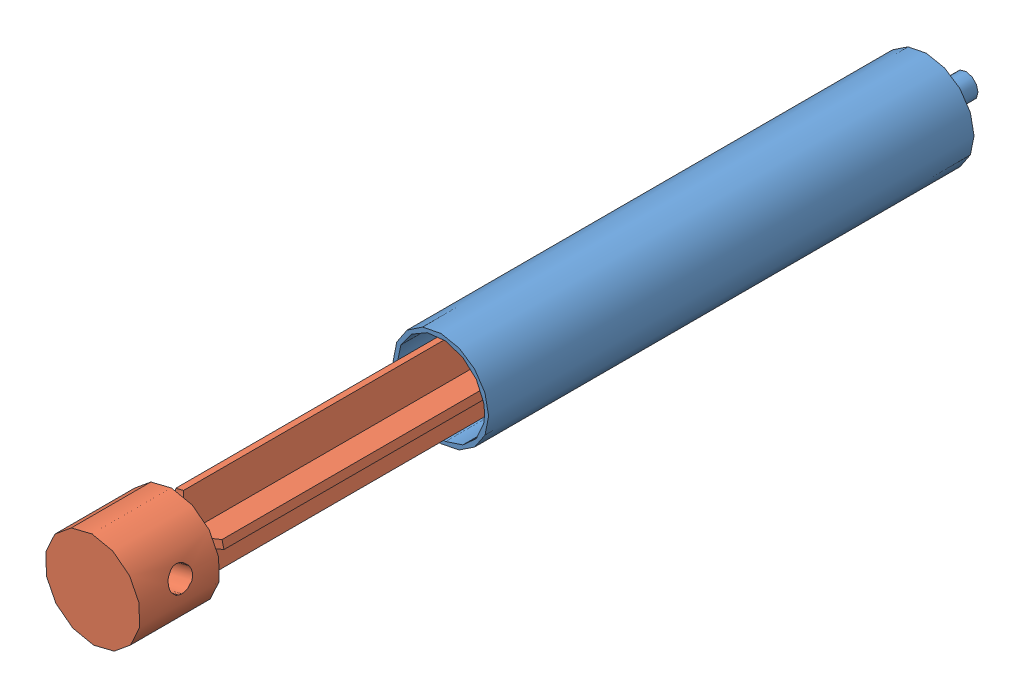
SolidWorks assembly syringe-base, configuration Default. Lengths in mm.
Overall size (18.45 18.45 139.39).
2 component instances, 2 part files, 3 mates.
Components (placement in the parent):
- sr-cylinder-1: sr-cylinder [Default] at (30.2101 49.0436 27.0158) size (15.24 15.24 83.82)
- sr-plunger-1: sr-plunger [Default] at (30.2101 49.0436 59.7213) x (-0.970784 -0.239954 0) z (0 0 1) size (15.24 15.24 99.06)
Mates (geometry in assembly coordinates):
- Concentric1: concentric aligned: cylinder of sr-cylinder-1 through (30.2101 49.0436 103.2158) axis (0 0 -1) radius 6.985; cylinder of sr-plunger-1 through (30.2101 49.0436 62.2613) axis (0 0 -1) radius 6.985
- LimitDistance1: limit distance = 32.7055 mm anti-aligned: plane of sr-plunger-1 through (30.2101 49.0436 59.7213) normal (0 0 -1); plane of sr-cylinder-1 through (30.2101 49.0436 27.0158) normal (0 0 1)
- Concentric2: concentric aligned: cylinder of sr-cylinder-1 through (30.2101 49.0436 103.2158) axis (0 0 -1) radius 7.62; cylinder of sr-plunger-1 through (30.2101 49.0436 158.7813) axis (0 0 -1) radius 7.62
